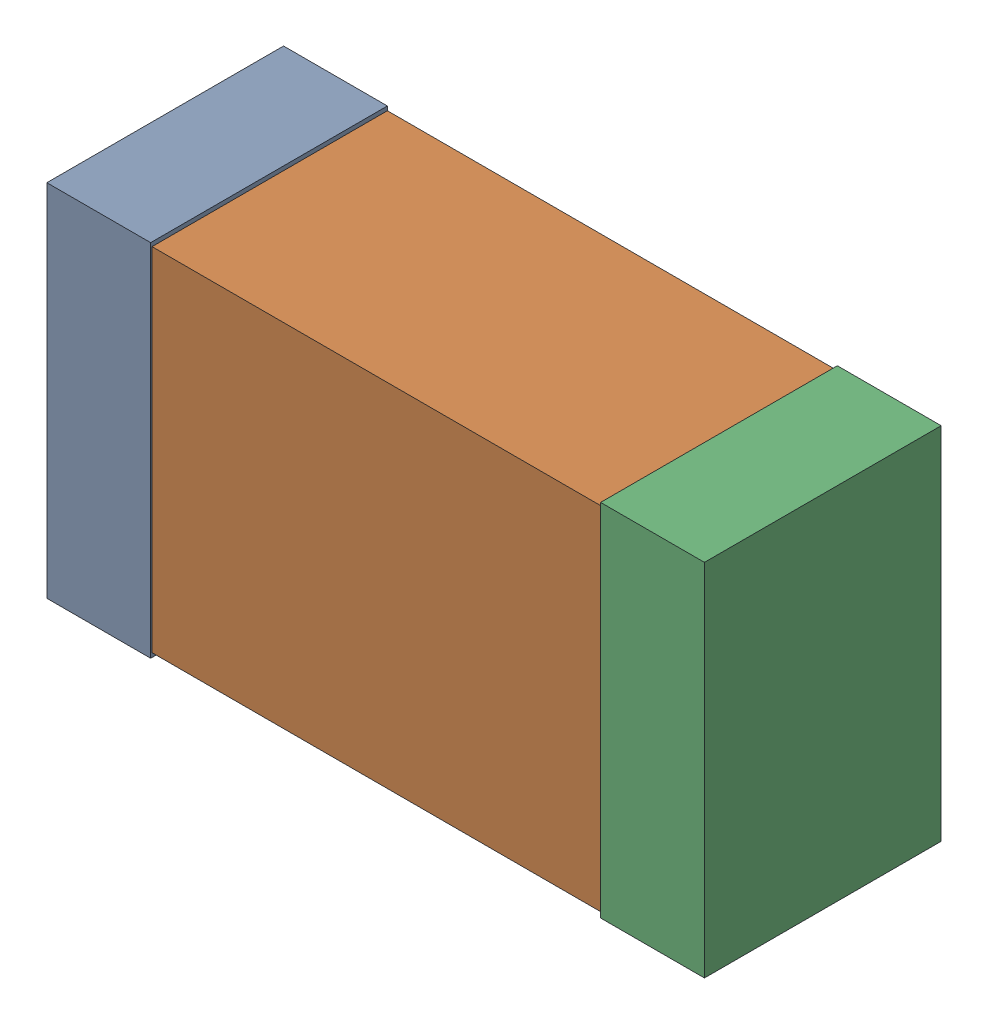
SolidWorks assembly C13_0Kanaloa_v2.0.0_Motor, configuration Default. Lengths in mm.
Overall size (2.38 1.3 0.85).
6 component instances, 2 part files, 0 mates.
Components (placement in the parent):
- 352877648-1: 352877648 [Default] at (59.69 59.69 0) size (0.38 1.3 0.85)
  - Extruded_14-1: Extruded_14 [Default] at origin size (0.38 1.3 0.85)
- 352877392-1: 352877392 [Default] at (60.69 59.69 0) size (2.2 1.27 0.85)
  - Extruded_15-1: Extruded_15 [Default] at origin size (2.2 1.27 0.85)
- 352877648-2: 352877648 [Default] at (61.69 59.69 0) size (0.38 1.3 0.85)
  - Extruded_14-1: Extruded_14 [Default] at origin size (0.38 1.3 0.85)
